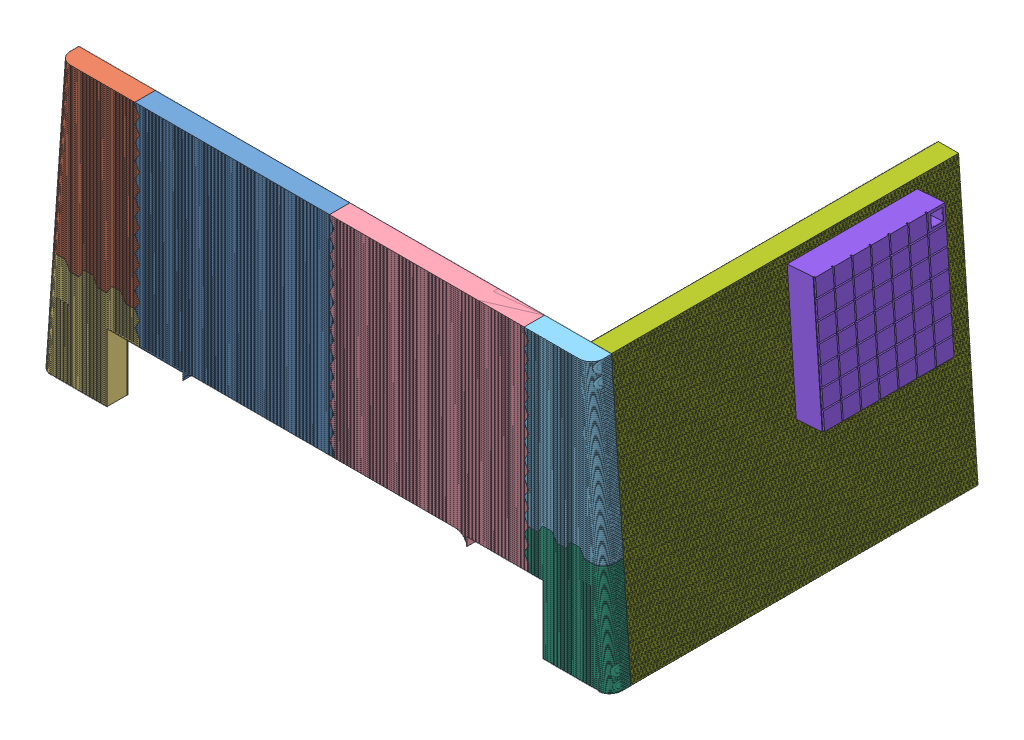
SolidWorks assembly mur_complete_gauche-droit, configuration Default. Lengths in mm.
Overall size (679.84 323.31 424.57).
23 component instances, 15 part files, 18 mates.
Components (placement in the parent):
- mur_droit-gauche_split_1of2_subsplit_1of3-1: mur_droit-gauche_split_1of2_subsplit_1of3 [Default] at (144.11 306.1438 508.3312) size (600.69 249.99 24)
- mur_droit-gauche_split_1of2_subsplit_2of3-1: mur_droit-gauche_split_1of2_subsplit_2of3 [Default] at (144.11 306.1438 508.3312) size (621.64 206.26 24)
- mur_droit-gauche_split_1of2_subsplit_3of3-1: mur_droit-gauche_split_1of2_subsplit_3of3 [Default] at (144.11 306.1438 508.3312) size (630.07 320.77 24.57)
- mur_droit-gauche_split_2of2_subsplit_1of3-1: mur_droit-gauche_split_2of2_subsplit_1of3 [Default] at (144.11 306.1438 508.3312) size (600.69 251.99 24)
- mur_droit-gauche_split_2of2_subsplit_2of3-1: mur_droit-gauche_split_2of2_subsplit_2of3 [Default] at (144.11 306.1438 508.3312) size (621.22 197.14 24)
- mur_droit-gauche_split_2of2_subsplit_3of3-1: mur_droit-gauche_split_2of2_subsplit_3of3 [Default] at (144.11 306.1438 508.3312) size (630.57 320.93 24.57)
- R-03-01-1: R-03-01 [Default] at (493.0954 335.91 295.2124) x (1 0 0) z (0 0 -1) size (95.68 323.35 450.01)
  - Radiateur.STEP-1: Radiateur.STEP [Default] at origin size (95.68 323.35 450.01) (hidden)
    - Mur_largeur.STEP-1: Mur_largeur.STEP [Default] at (-64.9032 -140.3514 -216.6004) size (47.38 320 450) (hidden)
    - braquetterad2.STEP-1: braquetterad2.STEP [Default] at (-39.9032 -140.3514 233.3996) x (0 0 -1) z (-0.069756 -0.997564 0) size (30 48 30)
    - 05-Radiateur.STEP-1: 05-Radiateur.STEP [Default] at (-9.2242 -131.689 158.3996) x (0.069756 0.997564 0) z (0 0 1) size (300 30 300) (hidden)
    - braquetterad1.STEP-1: braquetterad1.STEP [Default] at (-19.6193 149.7217 233.3996) x (0 0 -1) z (-0.069756 -0.997564 0) size (30 48 30)
    - braquetterad2.STEP-2: braquetterad2.STEP [Default] at (-17.5266 179.6486 -216.6004) x (0 0 1) z (0.069756 0.997564 0) size (30 48 30)
    - braquetterad1.STEP-2: braquetterad1.STEP [Default] at (-37.8105 -110.4245 -216.6004) x (0 0 1) z (0.069756 0.997564 0) size (30 48 30)
    - tigerad.STEP-1: tigerad.STEP [Default] at (24.9501 170.6637 -191.6004) x (-0.267506 0.963556 0) z (0.963556 0.267506 0) size (2 400 2)
    - tigerad.STEP-2: tigerad.STEP [Default] at (3.4106 -137.3656 208.3996) x (1 0 0) z (0 1 0) size (2 400 2)
    - Springs.STEP-1: Springs.STEP [Default] at (0.7048 -136.4477 4.1759) x (1 0 0) z (0 0.999962 -0.008727) size (7 191 8.08)
    - Springs.STEP-2: Springs.STEP [Default] at (22.024 170.9453 1.098) x (1 0 0) z (0 0.999962 -0.008727) size (7 191 8.08)
    - Springs.STEP-3: Springs.STEP [Default] at (24.2732 170.9212 201.9899) x (1 0 0) z (0 0.999962 -0.008727) size (7 191 8.08)
    - Springs.STEP-4: Springs.STEP [Default] at (2.2292 -136.5481 199.8891) x (1 0 0) z (0 0.999962 -0.008727) size (7 191 8.08)
    - rightshield.STEP-1: rightshield.STEP [Default] at (-39.0719 -128.4631 173.3565) x (0.997564 -0.069756 0) z (-0.069756 -0.997564 0) size (30 20 300) (hidden)
- mur_avant-arriere_shell-1: mur_avant-arriere_shell [Default] at (451.9144 156.215 488.2128) x (-0.997564 -0.069756 0) z (0 0 -1) size (24 322.42 400)
- Radiateur_placeholder-1: Radiateur_placeholder [Default] at (453.9442 465.5063 136.8128) x (0 0 1) z (-0.069756 0.997564 0) size (150 32 150)
Mates (geometry in assembly coordinates):
- Coincident3: coincident: line of mur_droit-gauche_split_1of2_subsplit_1of3-1 through (-68.2503 466.1667 512.2128) axis (0 1 0); plane of mur_droit-gauche_split_1of2_subsplit_2of3-1 through (-103.89 306.1438 512.2128) normal (0 0 1)
- Coincident4: coincident aligned: plane of mur_droit-gauche_split_1of2_subsplit_1of3-1 through (-73.89 306.1438 512.2128) normal (0 0 1); plane of mur_droit-gauche_split_1of2_subsplit_3of3-1 through (-83.89 306.1438 512.2128) normal (0 0 1)
- Coincident6: coincident aligned: line of mur_droit-gauche_split_1of2_subsplit_1of3-1 through (151.8092 476.2614 488.6128) axis (0 0 1); line of mur_droit-gauche_split_2of2_subsplit_1of3-1 through (151.8092 476.2614 488.6128) axis (0 0 1)
- Coincident7: coincident aligned: plane of mur_droit-gauche_split_1of2_subsplit_1of3-1 through (138.11 306.1438 512.2128) normal (0 0 1); plane of mur_droit-gauche_split_2of2_subsplit_1of3-1 through (144.11 306.1438 512.2128) normal (0 0 1)
- Coincident8: coincident aligned: line of mur_droit-gauche_split_2of2_subsplit_1of3-1 through (376.0592 476.2614 511.8128) axis (0 0 -1); line of mur_droit-gauche_split_2of2_subsplit_2of3-1 through (376.0592 476.2614 512.0128) axis (0 0 -1)
- Coincident9: coincident aligned: plane of mur_droit-gauche_split_2of2_subsplit_1of3-1 through (366.11 306.1438 512.2128) normal (0 0 1); plane of mur_droit-gauche_split_2of2_subsplit_2of3-1 through (372.11 306.1438 512.2128) normal (0 0 1)
- Coincident11: coincident aligned: line of mur_droit-gauche_split_2of2_subsplit_2of3-1 through (381.3997 279.2614 511.8128) axis (0 0 -1); line of mur_droit-gauche_split_2of2_subsplit_3of3-1 through (381.3997 279.2614 511.8128) axis (0 0 -1)
- Coincident12: coincident aligned: plane of mur_droit-gauche_split_2of2_subsplit_2of3-1 through (392.11 306.1438 512.2128) normal (0 0 1); plane of mur_droit-gauche_split_2of2_subsplit_3of3-1 through (396.11 306.1438 512.2128) normal (0 0 1)
- Coincident13: coincident aligned: plane of mur_droit-gauche_split_2of2_subsplit_2of3-1 through (455.9834 436.3449 488.6128) normal (0.997564 0.069756 0); plane of Radiateur-1/Radiateur.STEP-1/Mur_largeur.STEP-1 through (475.5688 156.2614 61.8128) normal (0.997564 0.069756 0)
- Coincident14: coincident aligned: plane of mur_droit-gauche_split_2of2_subsplit_2of3-1 through (296.7439 222.7614 511.8128) normal (0 0 1); plane of Radiateur-1/Radiateur.STEP-1/Mur_largeur.STEP-1 through (428.1922 476.2614 511.8128) normal (0 0 1)
- Coincident15: coincident: plane of mur_droit-gauche_split_2of2_subsplit_2of3-1 through (449.3991 476.2614 508.0296) normal (0 1 0); line of Radiateur-1/Radiateur.STEP-1/Mur_largeur.STEP-1 through (453.1922 476.2614 61.8128) axis (0 0 1)
- Coincident16: coincident anti-aligned: plane of mur_droit-gauche_split_2of2_subsplit_2of3-1 through (442.11 306.1438 488.2128) normal (0 0 -1); plane of mur_avant-arriere_shell-1 through (451.9144 156.215 488.2128) normal (0 0 1)
- Coincident17: coincident aligned: plane of mur_droit-gauche_split_2of2_subsplit_2of3-1 through (455.9834 436.3449 488.6128) normal (0.997564 0.069756 0); plane of mur_avant-arriere_shell-1 through (475.5701 156.2429 488.2128) normal (0.997564 0.069756 0)
- Coincident18: coincident: plane of mur_droit-gauche_split_2of2_subsplit_2of3-1 through (449.3991 476.2614 508.0296) normal (0 1 0); line of mur_avant-arriere_shell-1 through (453.1922 476.2614 476.2128) axis (0 0 -1)
- Coincident19: coincident aligned: plane of Radiateur-1/Radiateur.STEP-1/05-Radiateur.STEP-1 through (453.9442 465.5063 136.8128) normal (-0.069756 0.997564 0); plane of Radiateur_placeholder-1 through (483.8712 467.599 136.8128) normal (-0.069756 0.997564 0)
- Coincident20: coincident anti-aligned: plane of mur_avant-arriere_shell-1 through (475.5701 156.2429 440.2128) normal (0.997564 0.069756 0); plane of Radiateur_placeholder-1 through (453.9442 465.5063 136.8128) normal (-0.997564 -0.069756 0)
- Coincident22: coincident anti-aligned: plane of mur_droit-gauche_split_2of2_subsplit_1of3-1 through (381.3997 120.7013 538.3312) normal (1 0 0); plane of mur_droit-gauche_split_2of2_subsplit_3of3-1 through (381.3997 242.2614 538.3312) normal (-1 0 0)
- Coincident23: coincident anti-aligned: plane of mur_droit-gauche_split_1of2_subsplit_1of3-1 through (157.1497 120.7013 488.6128) normal (1 0 0); plane of mur_droit-gauche_split_2of2_subsplit_1of3-1 through (157.1497 242.2614 488.6128) normal (-1 0 0)
